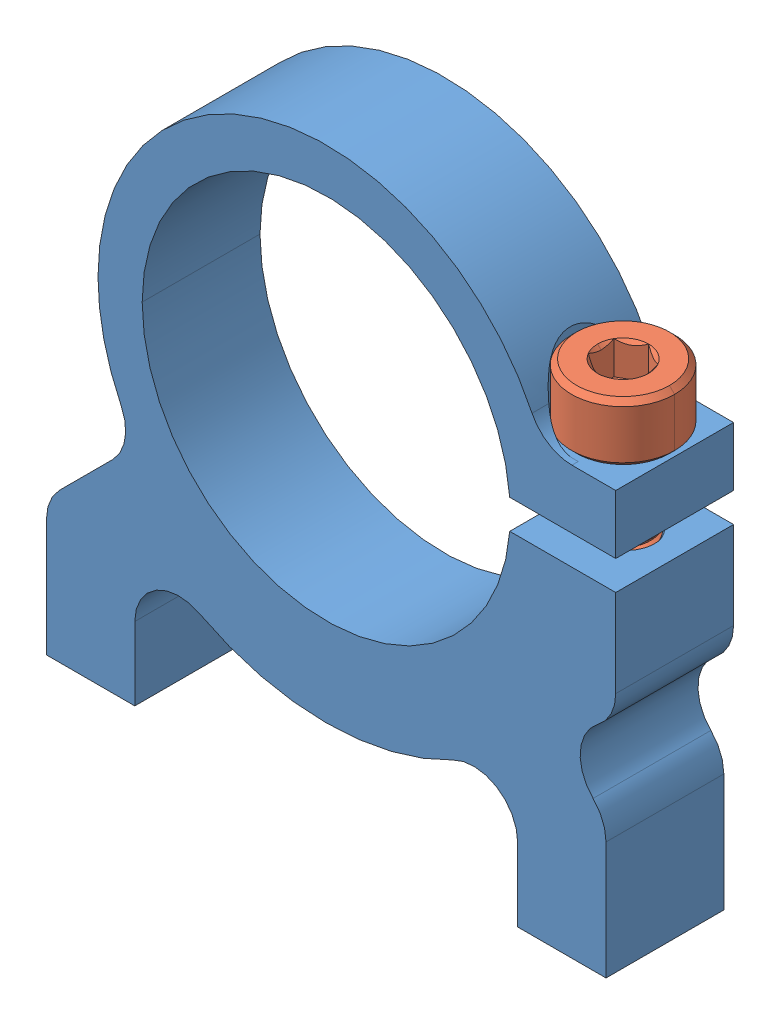
SolidWorks assembly 1-Side, 2-Post Clamping Mount (25mm Bore)1400-0032-0025, configuration Default. Lengths in mm.
Overall size (38.66 39.51 8).
2 component instances, 2 part files, 0 mates.
Components (placement in the parent):
- 1400-0032-0025.STEP-1: 1400-0032-0025.STEP [Default] at (-36.3751 25.389 0.7434) size (38.66 39.51 8)
- 2800-0004-0010_90128A207.STEP-1: 2800-0004-0010_90128A207.STEP [Default] at (-20.2151 20.389 4.7434) x (1 0 0) z (0 -1 0) size (7 7 14.01)
